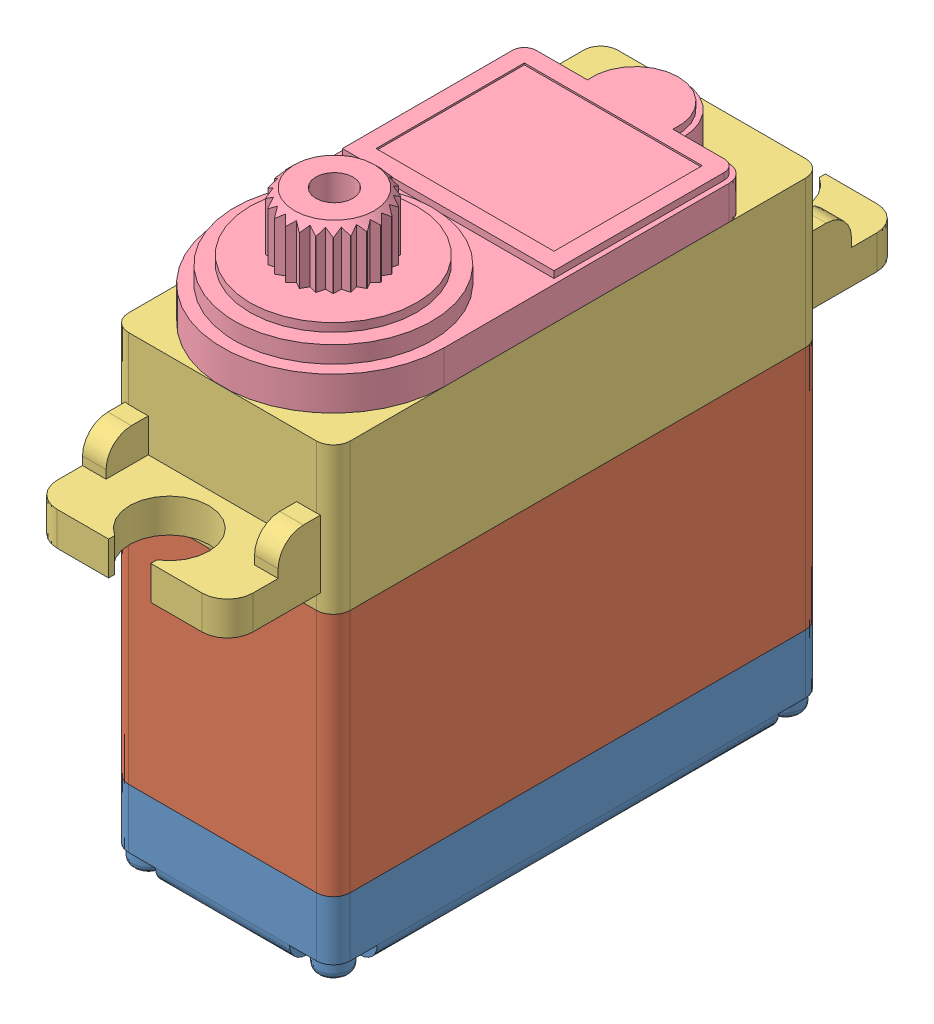
SolidWorks assembly HS85MG, configuration Default. Lengths in mm.
Overall size (13.15 34.62 40).
4 component instances, 4 part files, 6 mates.
Components (placement in the parent):
- HS85MG_bottom-1: HS85MG_bottom [Default] at (-14.7907 -7.6082 11.4451) size (13.15 4.52 29)
- HS85MG_midle-1: HS85MG_midle [Default] at (-14.7907 -3.1082 11.4451) size (13.15 14.5 29)
- HS85MG_upper-1: HS85MG_upper [Default] at (-14.7907 11.3918 11.4451) size (13.15 8.7 40)
- HS85MG_top-1: HS85MG_top [Default] at (-14.7907 20.0918 11.4701) size (13.15 6.9 27.33)
Mates (geometry in assembly coordinates):
- Coincident1: coincident aligned: line of HS85MG_bottom-1 through (-20.3657 -3.1082 25.9451) axis (1 0 0); line of HS85MG_midle-1 through (-20.3657 -3.1082 25.9451) axis (1 0 0)
- Coincident2: coincident aligned: line of HS85MG_bottom-1 through (-8.2157 -3.1082 24.9451) axis (0 0 -1); line of HS85MG_midle-1 through (-8.2157 -3.1082 24.9451) axis (0 0 -1)
- Coincident3: coincident aligned: line of HS85MG_midle-1 through (-20.3657 11.3918 25.9451) axis (1 0 0); line of HS85MG_upper-1 through (-20.3657 11.3918 25.9451) axis (1 0 0)
- Coincident4: coincident aligned: line of HS85MG_midle-1 through (-8.2157 11.3918 24.9451) axis (0 0 -1); line of HS85MG_upper-1 through (-8.2157 11.3918 24.9451) axis (0 0 -1)
- Coincident5: coincident aligned: line of HS85MG_upper-1 through (-8.2157 20.0918 24.9451) axis (0 0 -1); line of HS85MG_top-1 through (-8.2157 20.0918 19.3701) axis (0 0 -1)
- Coincident6: coincident: moEndPointRef_w of HS85MG_upper-1; moEndPointRef_w of HS85MG_top-1
